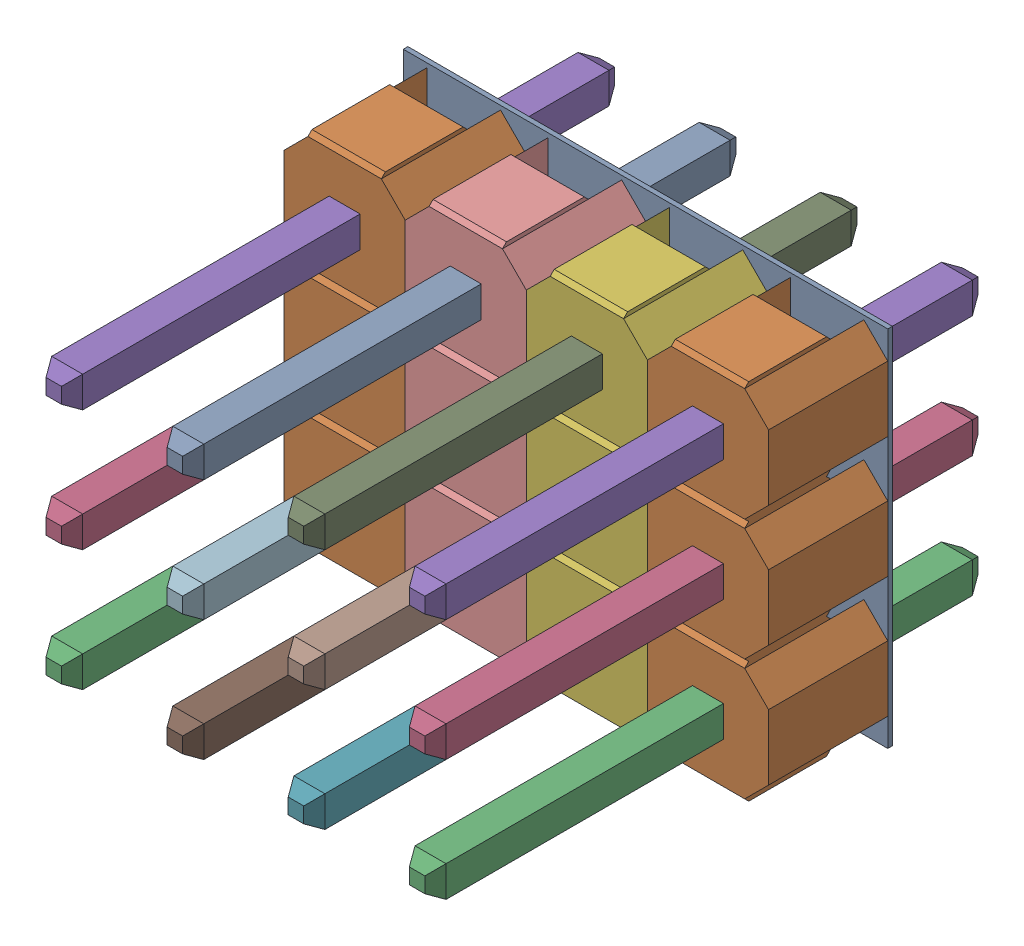
SolidWorks assembly PCB, configuration ﾃﾞﾌｫﾙﾄ. Lengths in mm.
Overall size (10.16 7.62 11.6).
10 component instances, 2 part files, 0 mates.
Components (placement in the parent):
- Board-1: Board [ﾃﾞﾌｫﾙﾄ] at origin size (10.16 7.62 0.1)
  - Open CASCADE STEP translator 6.8 6.1.1-1: Open CASCADE STEP translator 6.8 6.1.1 [ﾃﾞﾌｫﾙﾄ] at (0 0 -0.0965) size (10.16 7.62 0.1)
- Z_RST3-1: Z_RST3 [ﾃﾞﾌｫﾙﾄ] at origin size (2.54 7.62 11.6)
  - DS1021-1x3SF11-1: DS1021-1x3SF11 [ﾃﾞﾌｫﾙﾄ] at (8.8901 1.2699 0) x (0 1 0) z (0 0 1) size (7.62 2.54 11.6)
- Z_RST2-1: Z_RST2 [ﾃﾞﾌｫﾙﾄ] at origin size (2.54 7.62 11.6)
  - DS1021-1x3SF11-1: DS1021-1x3SF11 [ﾃﾞﾌｫﾙﾄ] at (6.3501 1.2699 0) x (0 1 0) z (0 0 1) size (7.62 2.54 11.6)
- Z_RST1-1: Z_RST1 [ﾃﾞﾌｫﾙﾄ] at origin size (2.54 7.62 11.6)
  - DS1021-1x3SF11-1: DS1021-1x3SF11 [ﾃﾞﾌｫﾙﾄ] at (3.8101 1.2699 0) x (0 1 0) z (0 0 1) size (7.62 2.54 11.6)
- Z_RST-1: Z_RST [ﾃﾞﾌｫﾙﾄ] at origin size (2.54 7.62 11.6)
  - DS1021-1x3SF11-1: DS1021-1x3SF11 [ﾃﾞﾌｫﾙﾄ] at (1.2701 1.2699 0) x (0 1 0) z (0 0 1) size (7.62 2.54 11.6)
